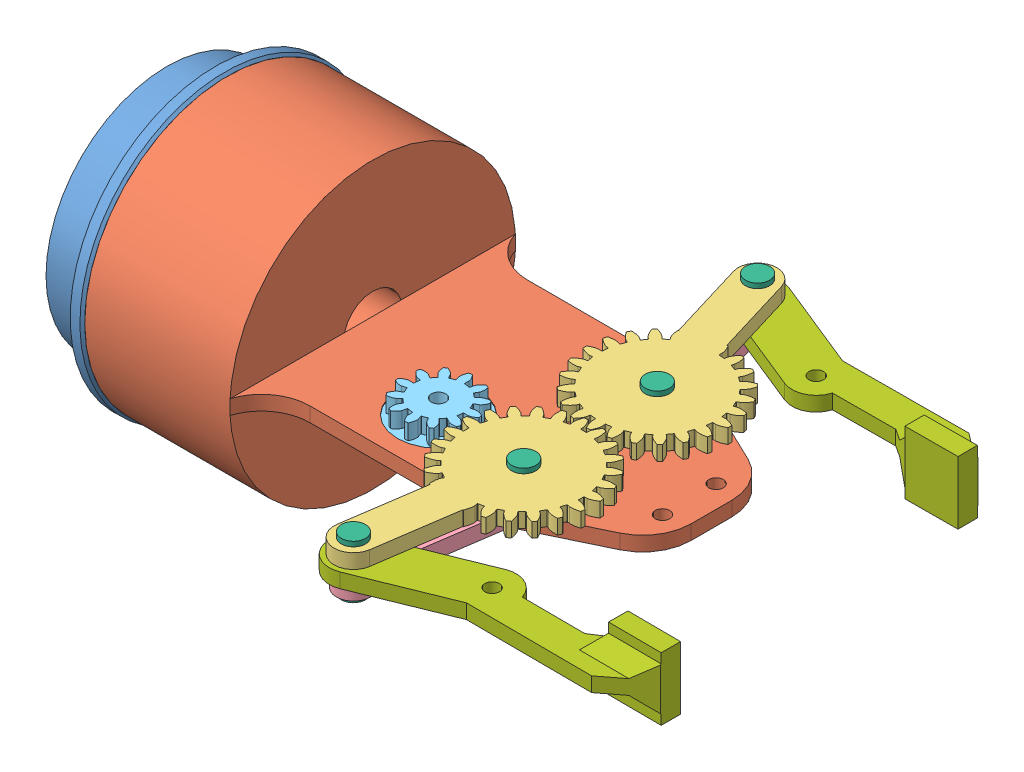
SolidWorks assembly armassembly, configuration Default. Lengths in mm.
Overall size (137.5 60 98.88).
14 component instances, 8 part files, 32 mates.
Components (placement in the parent):
- TAXIS_FLANGE-1: TAXIS_FLANGE [Default] at (-0.4743 35.3462 52.0844) size (12.5 60 60)
- Part224-1: Part224 [Default] at origin size (110 59 60.05)
- Part250-1: Part250 [Default] at origin
- 1-1: 1 [Default] at (83.7306 42.8462 78.0981) x (-0.910094 0 -0.414402) z (0 -1 0) size (39.07 41.91 3)
- ce-1: ce [Default] at (36.6054 36.8462 -32.2912) x (0.635408 0 -0.772177) z (0 -1 0) size (24.22 32.78 3)
- cog-1: cog [Default] at (83.2887 33.6462 53.8489) x (-0.780037 0 -0.625733) z (0 1 0) size (17 17 6.2)
- nut-1: nut [Default] at (143.3282 36.8462 80.7667) x (-0.167526 0 0.985868) z (0 -1 0) size (5 5 11)
- 3new-1: 3new [Default] at (90.6825 33.8462 40.0034) x (-0.000603 0 1) z (-1 0 -0.000603) size (18.25 13 59.52)
- 1-2: 1 [Default] at (106.9527 42.8462 31.2592) x (0.647174 0 0.762342) z (0 -1 0) size (39.07 41.91 3)
- 3new-2: 3new [Default] at (95.1296 36.8462 65.1594) x (-0.000515 0 -1) z (-1 0 0.000515) size (18.25 13 59.52)
- ce-2: ce [Default] at (102.6136 36.8462 151.2081) x (-0.903632 0 0.42831) z (0 -1 0) size (24.22 32.78 3)
- nut-2: nut [Default] at (92.2656 36.8462 -19.7156) x (1 0 0) z (0 -1 0) size (5 5 11)
- nut-3: nut [Default] at (83.302 36.8462 -49.3915) x (1 0 0) z (0 -1 0) size (5 5 11)
- nut-4: nut [Default] at (27.9036 36.8462 76.3053) x (0.261913 0 -0.965091) z (0 -1 0) size (5 5 11)
Mates (geometry in assembly coordinates):
- Parallel1: parallel anti-aligned: plane of Part224^armassembly-1 through (112.0257 36.8462 74.5844) normal (0 1 0); plane of 1-1 through (87.0257 36.8462 38.2844) normal (0 -1 0)
- Parallel2: parallel aligned: plane of Part224^armassembly-1 through (112.0257 36.8462 74.5844) normal (0 1 0); plane of 3new-1 through (118.9813 36.8462 16.0601) normal (0 1 0)
- Parallel3: parallel anti-aligned: plane of Part224^armassembly-1 through (112.0257 36.8462 74.5844) normal (0 1 0); plane of ce-1 through (90.7699 30.8462 23.2434) normal (0 -1 0)
- Parallel4: parallel anti-aligned: plane of Part224^armassembly-1 through (112.0257 36.8462 74.5844) normal (0 1 0); plane of 1-2 through (87.0257 36.8462 65.8844) normal (0 -1 0)
- Parallel5: parallel aligned: plane of Part224^armassembly-1 through (112.0257 36.8462 74.5844) normal (0 1 0); plane of cog-1 through (66.4257 39.8462 62.8844) normal (0 1 0)
- Parallel6: parallel anti-aligned: plane of Part224^armassembly-1 through (112.0257 36.8462 74.5844) normal (0 1 0); plane of ce-2 through (89.1654 30.8462 81.236) normal (0 -1 0)
- Parallel7: parallel anti-aligned: plane of Part224^armassembly-1 through (112.0257 36.8462 74.5844) normal (0 1 0); plane of nut-1 through (85.0961 29.8462 64.2948) normal (0 -1 0)
- Parallel8: parallel anti-aligned: plane of Part224^armassembly-1 through (112.0257 36.8462 74.5844) normal (0 1 0); plane of 3new-2 through (116.7672 33.8462 93.1146) normal (0 -1 0)
- Coincident9: coincident anti-aligned: plane of Part224^armassembly-1 through (112.0257 36.8462 74.5844) normal (0 1 0); plane of 1-2 through (87.0257 36.8462 65.8844) normal (0 -1 0)
- Coincident10: coincident anti-aligned: plane of Part224^armassembly-1 through (112.0257 36.8462 74.5844) normal (0 1 0); plane of 1-1 through (87.0257 36.8462 38.2844) normal (0 -1 0)
- Coincident11: coincident aligned: plane of cog-1 through (66.4257 39.8462 62.8844) normal (0 1 0); plane of 1-2 through (87.0257 39.8462 65.8844) normal (0 1 0)
- Coincident12: coincident anti-aligned: plane of 1-2 through (87.0257 36.8462 65.8844) normal (0 -1 0); plane of 3new-2 through (116.7672 36.8462 93.1146) normal (0 1 0)
- Concentric1: concentric anti-aligned: cylinder of 1-2 through (91.305 39.8462 96.5876) axis (0 -1 0) radius 1.5; circle of 3new-2
- Coincident14: coincident anti-aligned: plane of 1-1 through (87.0257 36.8462 38.2844) normal (0 -1 0); plane of 3new-1 through (118.9813 36.8462 16.0601) normal (0 1 0)
- Concentric2: concentric anti-aligned: circle of 1-1; circle of 3new-1
- Concentric3: concentric anti-aligned: circle of Part224^armassembly-1; circle of 1-2
- Concentric4: concentric anti-aligned: circle of Part224^armassembly-1; circle of 1-1
- Concentric5: concentric anti-aligned: circle of Part224^armassembly-1; circle of cog-1
- Coincident19: coincident anti-aligned: plane of Part224^armassembly-1 through (112.0257 33.8462 74.5844) normal (0 -1 0); plane of ce-1 through (90.7699 33.8462 23.2434) normal (0 1 0)
- Coincident20: coincident anti-aligned: plane of Part224^armassembly-1 through (112.0257 33.8462 74.5844) normal (0 -1 0); plane of ce-2 through (89.1654 33.8462 81.236) normal (0 1 0)
- Concentric6: concentric aligned: circle of Part224^armassembly-1; circle of ce-1
- Concentric7: concentric aligned: circle of ce-1; circle of 3new-1
- Concentric8: concentric aligned: circle of Part224^armassembly-1; circle of ce-2
- Concentric9: concentric anti-aligned: circle of 3new-2; circle of ce-2
- Concentric18: concentric anti-aligned: circle of 1-1; circle of nut-2
- Concentric19: concentric anti-aligned: circle of nut-1; circle of 1-2
- Concentric20: concentric anti-aligned: circle of 1-1; circle of nut-3
- Concentric21: concentric anti-aligned: circle of 1-2; circle of nut-4
- Coincident38: coincident anti-aligned: plane of 1-1 through (87.0257 39.8462 38.2844) normal (0 1 0); plane of nut-2 through (85.4343 39.8462 40.2125) normal (0 -1 0)
- Coincident39: coincident anti-aligned: plane of 1-1 through (87.0257 39.8462 38.2844) normal (0 1 0); plane of nut-3 through (92.9228 39.8462 10.1305) normal (0 -1 0)
- Coincident41: coincident anti-aligned: plane of nut-1 through (85.0961 39.8462 64.2948) normal (0 -1 0); plane of 1-2 through (87.0257 39.8462 65.8844) normal (0 1 0)
- Coincident42: coincident anti-aligned: plane of 1-2 through (87.0257 39.8462 65.8844) normal (0 1 0); plane of nut-4 through (92.749 39.8462 98.6284) normal (0 -1 0)
